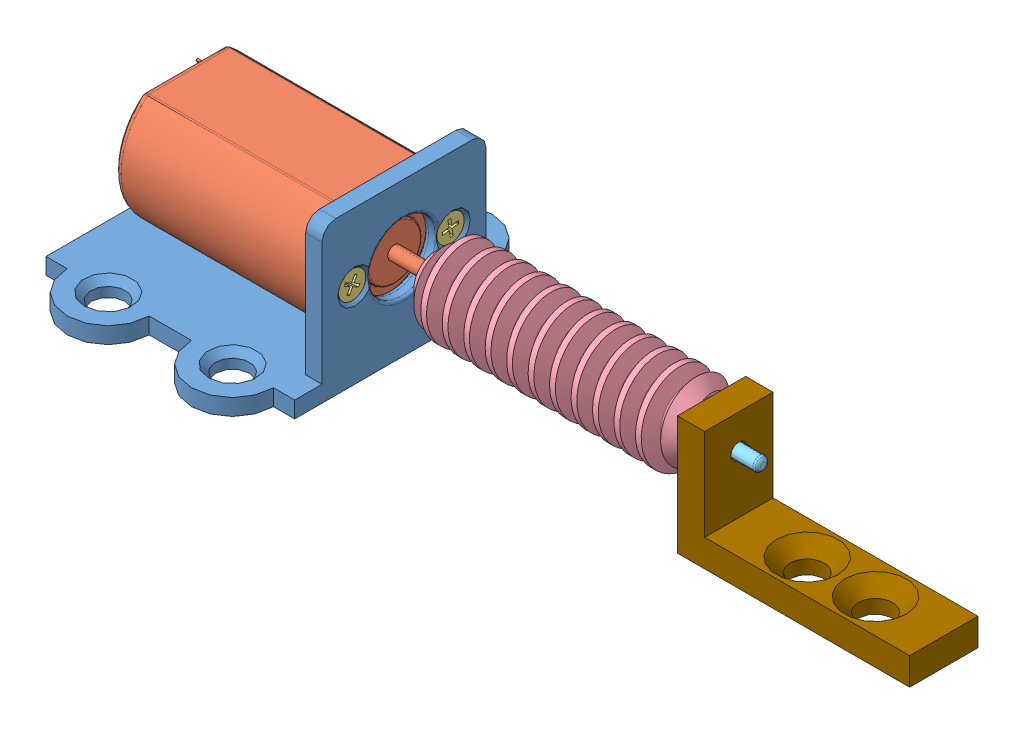
SolidWorks assembly Motor Stand ASSY, configuration Default. Lengths in mm.
Overall size (57.7 11.2 22).
16 component instances, 9 part files, 15 mates.
Components (placement in the parent):
- Motor stand-1: Motor stand [Default] at (14.5557 9.9986 19.1017) x (0 -1 0) z (0 0 1) size (11.2 18.28 22)
- PKN7EB105C motor-1: PKN7EB105C motor [Default] at (-0.4443 9.9986 19.1017) x (0 0 -1) z (0 -1 0) size (10 25.2 8)
- SNZF-M1_4-3-TBZ-1: SNZF-M1_4-3-TBZ [Default] at (15.1057 9.9986 15.5017) x (-1 0 0) z (0 -0.147104 0.989121) size (3 2 2)
- SNZF-M1_4-3-TBZ-2: SNZF-M1_4-3-TBZ [Default] at (15.1057 9.9986 22.7017) x (-1 0 0) z (0 -0.877398 0.479764) size (3 2 2)
- Worm 21-1: Worm 21 [GearTrax] at (28.0557 9.9986 19.1017) x (0 0 -1) z (1 0 0) size (6 6 21.1)
- 10mm shaft-1: 10mm shaft [Default] at (32.0557 9.9986 19.1017) x (0 0.407305 0.913292) z (1 0 0) size (1 1 10)
- W 618_1-1: W 618_1 [Default] at (38.1557 9.9986 19.1017) size (1 3 3)
  - W 618_1_PART1-1: W 618_1_PART1 [Default] at origin size (1 1.55 1.55)
  - W 618_1_PART2-1: W 618_1_PART2 [Default] at origin size (1 3 3)
  - W 618_1_PART3-1: W 618_1_PART3 [Default] at origin size (0.6 0.6 0.6)
  - W 618_1_PART3-2: W 618_1_PART3 [Default] x (1 0 0) z (0 0.866025 0.5) size (0.6 0.6 0.6)
  - W 618_1_PART3-3: W 618_1_PART3 [Default] x (1 0 0) z (0 0.866025 -0.5) size (0.6 0.6 0.6)
  - W 618_1_PART3-4: W 618_1_PART3 [Default] x (1 0 0) z (0 0 -1) size (0.6 0.6 0.6)
  - W 618_1_PART3-5: W 618_1_PART3 [Default] x (1 0 0) z (0 -0.866025 -0.5) size (0.6 0.6 0.6)
  - W 618_1_PART3-6: W 618_1_PART3 [Default] x (1 0 0) z (0 -0.866025 0.5) size (0.6 0.6 0.6)
- Bearing stand-2: Bearing stand [Default] at (40.2557 9.9986 19.1017) x (0 0 1) z (-1 0 0) size (5 8.7 17)
Mates (geometry in assembly coordinates):
- Concentric1: concentric anti-aligned: circle of Motor stand-1; circle of PKN7EB105C motor-1
- Coincident1: coincident anti-aligned: plane of Motor stand-1 through (14.5557 9.9986 19.1017) normal (-1 0 0); plane of PKN7EB105C motor-1 through (14.5557 9.9986 19.1017) normal (1 0 0)
- Concentric2: concentric aligned: circle of Motor stand-1; circle of SNZF-M1_4-3-TBZ-1
- Coincident2: coincident anti-aligned: plane of PKN7EB105C motor-1 through (12.5557 9.9986 15.5017) normal (1 0 0); plane of SNZF-M1_4-3-TBZ-1 through (12.5557 9.4882 15.4258) normal (-1 0 0)
- Concentric3: concentric aligned: circle of Motor stand-1; circle of SNZF-M1_4-3-TBZ-2
- Coincident3: coincident anti-aligned: plane of PKN7EB105C motor-1 through (12.5557 9.9986 22.7017) normal (1 0 0); plane of SNZF-M1_4-3-TBZ-2 through (12.5557 9.7511 22.2489) normal (-1 0 0)
- Concentric4: concentric anti-aligned: circle of PKN7EB105C motor-1; circle of Worm 21-1
- Distance1: distance = 3 mm anti-aligned: plane of PKN7EB105C motor-1 through (15.0557 9.9986 19.1017) normal (1 0 0); plane of Worm 21-1 through (18.0557 9.9986 19.1017) normal (-1 0 0)
- Concentric5: concentric anti-aligned: circle of Worm 21-1; circle of 10mm shaft-1
- Concentric6: concentric anti-aligned: cylinder of Worm 21-1 through (18.0557 9.9986 19.1017) axis (1 0 0) radius 0.45; cylinder of 10mm shaft-1 through (42.0557 9.9986 19.1017) axis (-1 0 0) radius 0.5
- Distance3: distance = 6 mm anti-aligned: plane of Worm 21-1 through (38.0557 11.5864 19.1017) normal (1 0 0); plane of 10mm shaft-1 through (32.0557 9.9986 19.1017) normal (-1 0 0)
- Concentric7: concentric aligned: circle of 10mm shaft-1; circle of W 618_1-1/W 618_1_PART1-1
- Distance4: distance = 0.1 mm anti-aligned: plane of W 618_1-1/W 618_1_PART1-1 through (38.1557 10.7636 19.1017) normal (-1 0 0); plane of Worm 21-1 through (38.0557 11.5864 19.1017) normal (1 0 0)
- Concentric9: concentric aligned: circle of 10mm shaft-1; circle of Bearing stand-2
- Distance6: distance = 0.1 mm anti-aligned: plane of Bearing stand-2 through (39.2557 9.9986 19.1017) normal (-1 0 0); plane of W 618_1-1/W 618_1_PART2-1 through (39.1557 11.2453 19.1017) normal (1 0 0)
